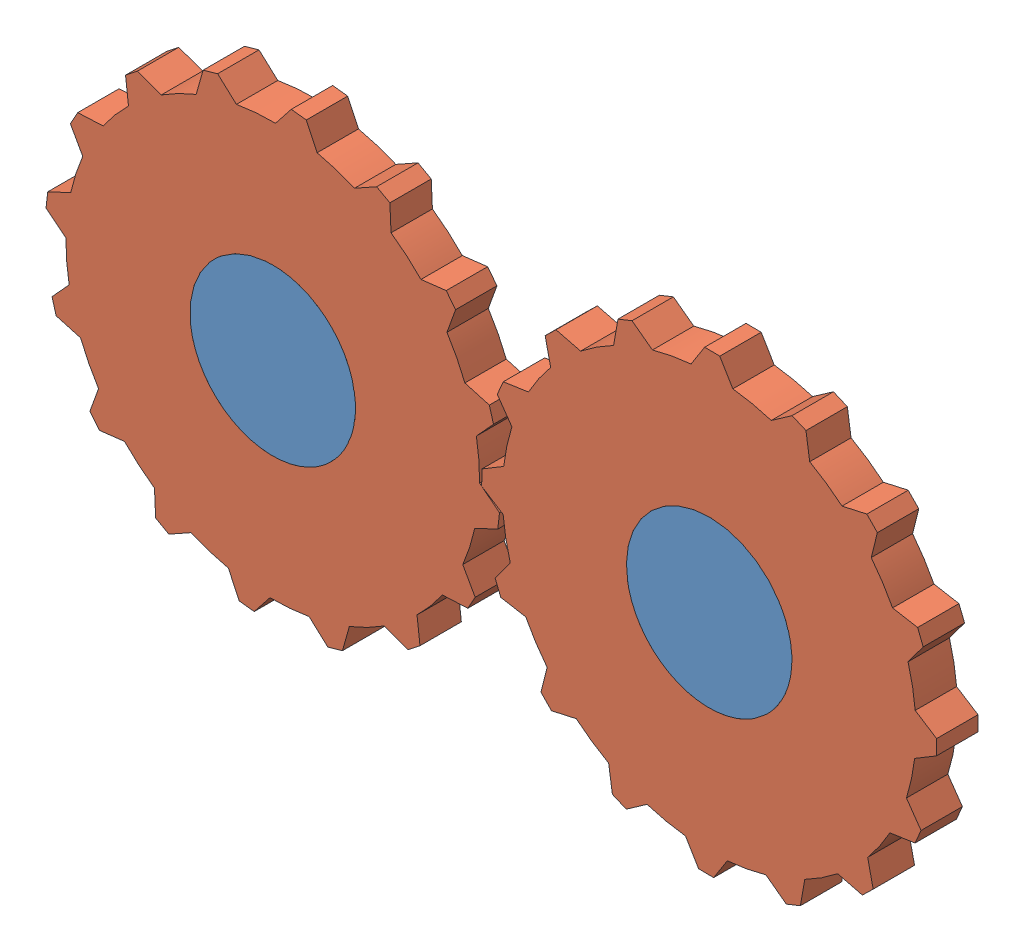
SolidWorks assembly Assem4, configuration Default. Lengths in mm.
Overall size (245.66 144.43 10).
3 component instances, 2 part files, 4 mates.
Components (placement in the parent):
- plane_3d_3-1: plane_3d_3 [Default] at (41.2696 82.5704 114.0541) size (145.5 40 10)
- gear_3d_2-1: gear_3d_2 [Default] at (-10.0994 77.5395 114.0541) x (0.274339 -0.961633 0) z (0 0 1) size (109.94 109.94 10)
- gear_3d_2-2: gear_3d_2 [Default] at (95.4006 77.5395 114.0541) x (0.395149 0.918617 0) z (0 0 1) size (109.94 109.94 10)
Mates (geometry in assembly coordinates):
- Coincident1: coincident aligned: plane of plane_3d_3-1 through (41.2696 82.5704 124.0541) normal (0 0 1); plane of gear_3d_2-1 through (-10.0994 77.5395 124.0541) normal (0 0 1)
- Coincident2: coincident aligned: plane of plane_3d_3-1 through (41.2696 82.5704 124.0541) normal (0 0 1); plane of gear_3d_2-2 through (95.4006 77.5395 124.0541) normal (0 0 1)
- Coincident3: coincident aligned: circle of plane_3d_3-1; circle of gear_3d_2-1
- Coincident4: coincident aligned: circle of plane_3d_3-1; circle of gear_3d_2-2
